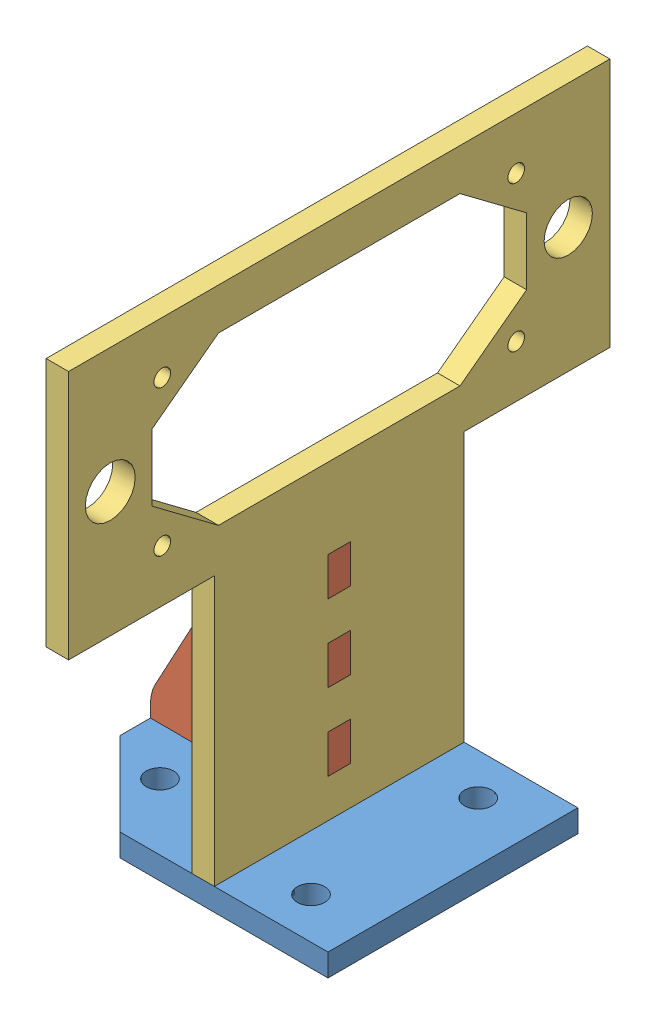
SolidWorks assembly Assem1_for_holder_for_laser_and_us_sensor, configuration Varsayılan. Lengths in mm.
Overall size (35 65 65).
3 component instances, 3 part files, 5 mates.
Components (placement in the parent):
- Part_A-1: Part_A [Varsayılan] at (3.1422 1.0257 29.0539) size (35 2.7 30)
- Part_B-2: Part_B [Varsayılan] at (-5.4061 15.8257 31.326) size (21.35 35 2.7)
- Part_C-1: Part_C [Varsayılan] at (5.2689 30.8257 30) size (2.7 65 65)
Mates (geometry in assembly coordinates):
- Coincident4: coincident anti-aligned: plane of Part_A-1 through (-1.1611 -1.6743 28.626) normal (-1 0 0); plane of Part_B-2 through (-1.1611 1.0257 28.626) normal (1 0 0)
- Coincident7: coincident anti-aligned: plane of Part_A-1 through (-4.8911 -1.6743 28.626) normal (0 0 1); plane of Part_B-2 through (-11.0811 2.4643 28.626) normal (0 0 -1)
- Coincident8: coincident anti-aligned: plane of Part_B-2 through (2.5689 14.8685 28.626) normal (1 0 0); plane of Part_C-1 through (2.5689 30.8257 30) normal (-1 0 0)
- Coincident9: coincident aligned: plane of Part_A-1 through (3.1422 -1.6743 29.0539) normal (0 -1 0); plane of Part_C-1 through (2.5689 -1.6743 19.2857) normal (0 -1 0)
- Coincident10: coincident aligned: plane of Part_A-1 through (13.9189 -1.6743 15) normal (0 0 -1); plane of Part_C-1 through (2.5689 1.0257 15) normal (0 0 -1)
